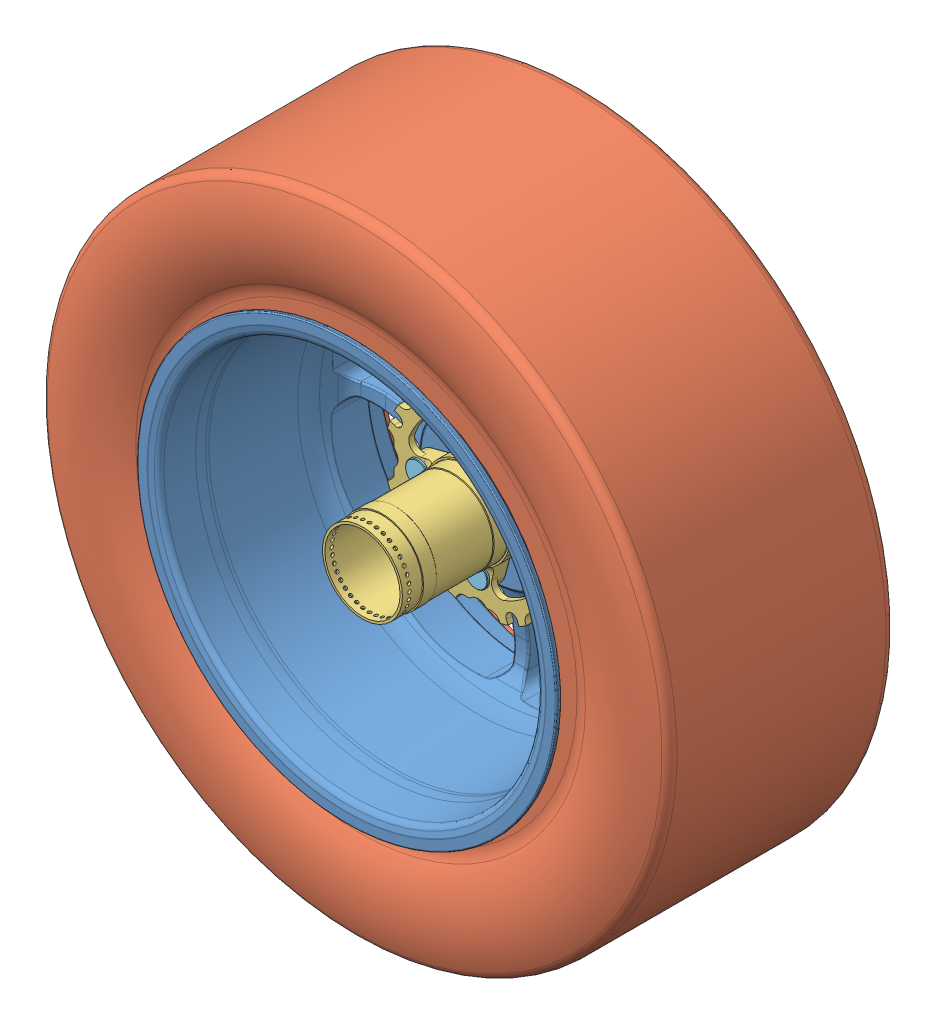
SolidWorks assembly LustroPUTM-S-SF-WT-Hub-Assembly, configuration Domyślna. Lengths in mm.
Overall size (533.4 533.4 204.86).
11 component instances, 5 part files, 0 mates.
Components (placement in the parent):
- LustroPUTM-S-WT-Wheel_Rim-1: LustroPUTM-S-WT-Wheel_Rim [Domyślna] at (14.7172 8.0447 -36.3013) x (0 0 1) z (-1 0 0) size (189.8 356.77 356.77)
- LustroPUTM-S-SF-WT-Tire-1: LustroPUTM-S-SF-WT-Tire [Default] at (14.7172 8.0447 -14.8013) x (1 0 0) z (0 1 0) size (533.4 203.2 533.4)
- LustroPUTM-S-SF-WT-Hub-v2-1: LustroPUTM-S-SF-WT-Hub-v2 [Domyślna] at (14.7172 8.0447 -53.3013) size (153.82 153.82 128.25)
- LustroPUTM-S-WT-WheelNut-1: LustroPUTM-S-WT-WheelNut [Domyślna] at (64.7172 8.0447 -76.5658) x (0.999858 -0.016869 0) z (-0.016869 -0.999858 0) size (25 27 25)
- LustroPUTM-S-WT-WheelNut-2: LustroPUTM-S-WT-WheelNut [Domyślna] at (14.7172 58.0447 -76.5658) x (-0.135726 -0.990746 0) z (-0.990746 0.135726 0) size (25 27 25)
- LustroPUTM-S-WT-WheelNut-3: LustroPUTM-S-WT-WheelNut [Domyślna] at (14.7172 -41.9553 -76.5658) x (0.999858 -0.016869 0) z (-0.016869 -0.999858 0) size (25 27 25)
- LustroPUTM-S-WT-WheelNut-4: LustroPUTM-S-WT-WheelNut [Domyślna] at (-35.2828 8.0447 -76.5658) x (0.999858 -0.016869 0) z (-0.016869 -0.999858 0) size (25 27 25)
- LustroPUTM-S-SF-WT-WH-wheel_stud-1: LustroPUTM-S-SF-WT-WH-wheel_stud [Domyślna] at (14.7172 58.0447 -21.3013) x (0 0 -1) z (0.985041 -0.172322 0) size (62 20 20)
- LustroPUTM-S-SF-WT-WH-wheel_stud-2: LustroPUTM-S-SF-WT-WH-wheel_stud [Domyślna] at (64.7172 8.0447 -21.3013) x (0 0 -1) z (0.985041 -0.172322 0) size (62 20 20)
- LustroPUTM-S-SF-WT-WH-wheel_stud-3: LustroPUTM-S-SF-WT-WH-wheel_stud [Domyślna] at (14.7172 -41.9553 -21.3013) x (0 0 -1) z (0.985041 -0.172322 0) size (62 20 20)
- LustroPUTM-S-SF-WT-WH-wheel_stud-4: LustroPUTM-S-SF-WT-WH-wheel_stud [Domyślna] at (-35.2828 8.0447 -21.3013) x (0 0 -1) z (0.985041 -0.172322 0) size (62 20 20)
